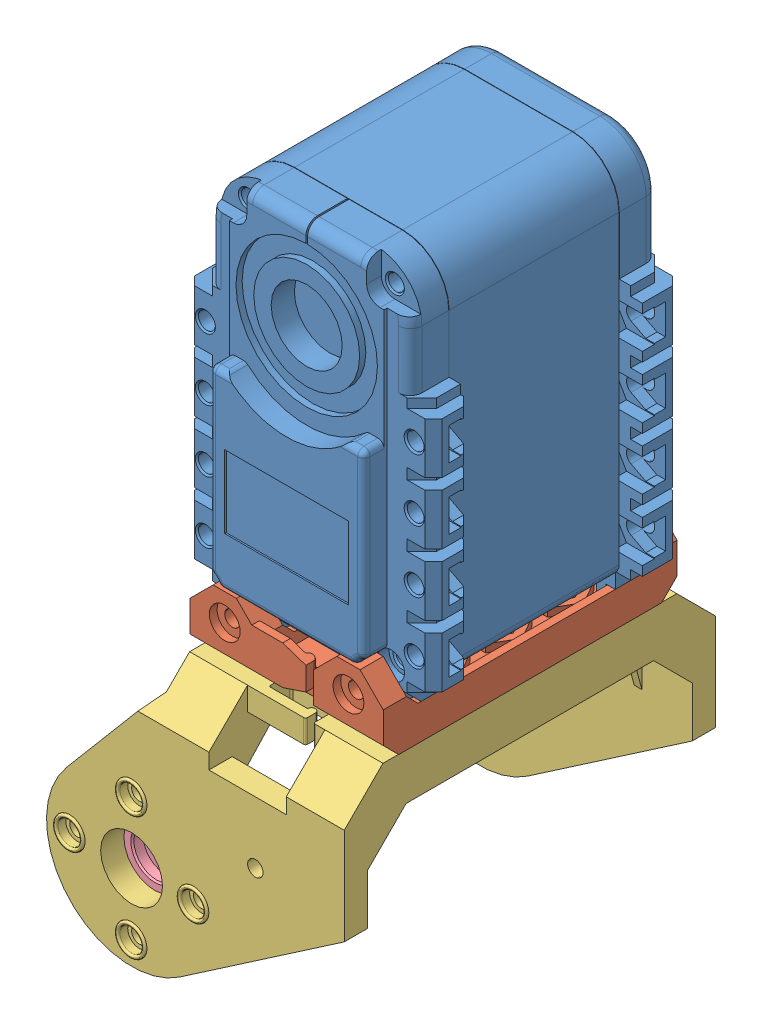
SolidWorks assembly Femur_left, configuration Default. Lengths in mm.
Overall size (42.04 87.04 48.5).
4 component instances, 4 part files, 10 mates.
Components (placement in the parent):
- ServoBody-1: ServoBody [Default] at origin size (32 50.04 38.67)
- F3-1: F3 [Default] at (0.5 -41.5 -13.4) x (-1 0 0) z (0 0 -1) size (25 9 38)
- F1-1: F1 [Default] at (-14.5426 -64.5 -13.3997) x (1 0 0) z (0 0 -1) size (38.5 34 48.5)
- ServoHorn-1: ServoHorn [Default] at (-14.5426 -64.5 -13.2697) size (22 22 6.71)
Mates (geometry in assembly coordinates):
- Coincident31: coordinate: point of ServoBody-1; point of assembly
- Concentric4: concentric anti-aligned: cylinder of F3-1 through (-7.5 -36 2.6) axis (0 0 1) radius 1; cylinder of ServoBody-1 through (-7.5 -36 2.4) axis (0 0 -1) radius 1.1
- Concentric5: concentric aligned: cylinder of F3-1 through (8.5 -36 2.6) axis (0 0 1) radius 1; cylinder of ServoBody-1 through (8.5 -36 0.6) axis (0 0 1) radius 1.1
- Coincident11: coincident anti-aligned: plane of F3-1 through (13 -41.5 2.6) normal (0 0 -1); plane of ServoBody-1 through (-14.996 -38.283 2.6) normal (0 0 1)
- Concentric6: concentric aligned: cylinder of F1-1 through (-14.5426 -56.5 -37.3997) axis (0 0 1) radius 1; cylinder of ServoHorn-1 through (-14.5426 -56.5 5.7603) axis (0 0 1) radius 1.05
- Concentric7: concentric aligned: cylinder of F1-1 through (-14.5426 -72.5 -37.3997) axis (0 0 1) radius 1; cylinder of ServoHorn-1 through (-14.5426 -72.5 5.7603) axis (0 0 1) radius 1.05
- Coincident12: coincident anti-aligned: plane of F1-1 through (-32.2664 -81.3342 7.6003) normal (0 0 -1); plane of ServoHorn-1 through (-25.9854 -53.0629 7.6003) normal (0 0 1)
- Coincident23: coincident anti-aligned: plane of F1-1 through (-12.042 -41.5 -37.3997) normal (0 1 0); plane of F3-1 through (15 -41.5 -0.65) normal (0 -1 0)
- Coincident27: coincident aligned: plane of F1-1 through (2.1897 -45.5 -18.4) normal (0 0 1); plane of F3-1 through (3.5 -38.5 -18.4) normal (0 0 1)
- Coincident28: coincident aligned: plane of F1-1 through (-2.5 -46 -18.4) normal (1 0 0); plane of F3-1 through (-2.5 -38.5 -8.4) normal (1 0 0)
